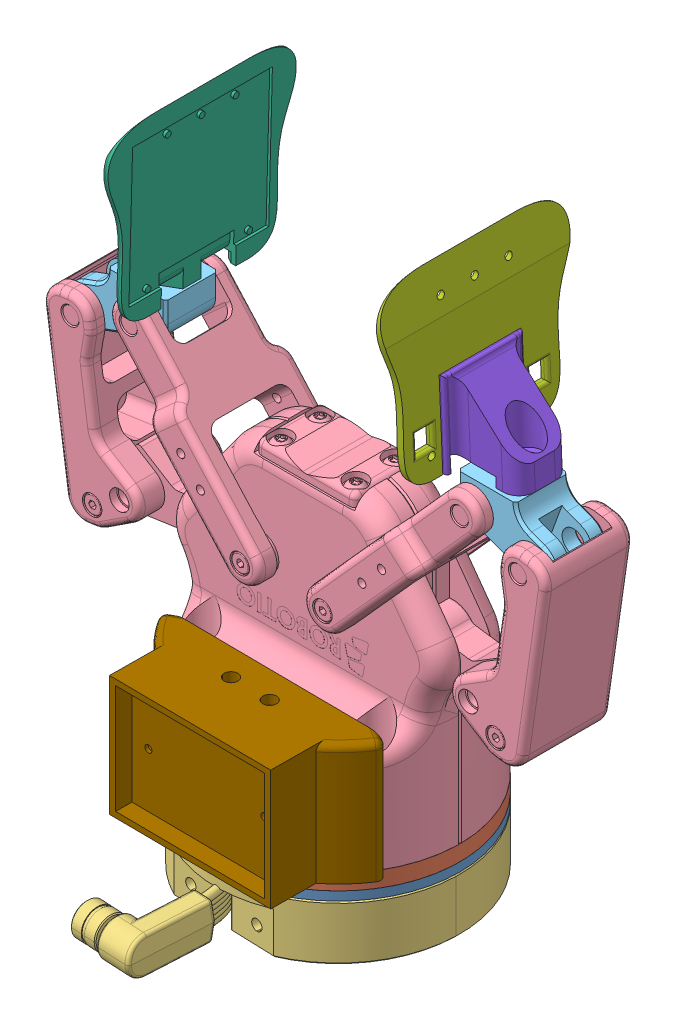
SolidWorks assembly GripperAssembly, configuration Default. Lengths in mm.
Overall size (154.57 188.05 107.75).
12 component instances, 9 part files, 12 mates.
Components (placement in the parent):
- PCB_flange-1: PCB_flange [Default] at (13.3416 26.4791 25.4276) size (75 9.2 71.41)
- PCB_flange_top-1: PCB_flange_top [Default] at (13.3416 33.9791 25.4276) x (1 0 0) z (0 -1 0) size (75 76 7.3)
- IO_20Coupling_20UR_20CB_20190807-1: IO_20Coupling_20UR_20CB_20190807 [Default] at (13.3416 19.4791 25.4276) x (-0.999452 0 -0.033096) z (0 1 0) size (75 105.33 17)
- 2F85-OPENED-NO_FINGER-1: 2F85-OPENED-NO_FINGER [Default] at (13.3416 33.8791 25.4276) size (154.57 113.82 75.02)
  - 2F85-OPENED-NO_20FINGER_20181108.STEP-1: 2F85-OPENED-NO_20FINGER_20181108.STEP [Default] at origin size (154.57 113.82 75.02)
    - C-A01-85-OPENED.STEP-1: C-A01-85-OPENED.STEP [Default] at origin size (154.57 113.32 75.02)
    - C-049-DISTALE_DISTALE.STEP-1: C-049-DISTALE_DISTALE.STEP [Default] at (-50.9079 103.9203 0) x (0.000045 1 0) z (0 0 -1) size (19.02 29.9 16.2)
    - C-049-DISTALE_DISTALE.STEP-2: C-049-DISTALE_DISTALE.STEP [Default] at (50.9079 103.9203 0) x (-0.000045 1 0) z (0 0 1) size (19.02 29.9 16.2)
- IRTouch_rigid-1: IRTouch_rigid [Default] at (-72.4754 198.4459 -64.5202) x (0 0 1) z (-0.026222 -0.999656 0) size (59.45 20.16 56.24)
- IRTouch_flex-1: IRTouch_flex [Default] at (56.9149 151.5392 3.6955) x (0 0 1) z (-0.043664 0.999046 0) size (60.09 4.5 55.96)
- IRTouch_flex_interface-1: IRTouch_flex_interface [Default] at (69.8172 161.6041 44.3771) x (0 0 -1) z (0.043664 -0.999046 0) size (24.8 19.45 26.62)
- Arduino_holder-2: Arduino_holder [Default] at (13.5774 36.0586 25.3763) x (-0.999962 0 -0.008727) z (0.008727 0 -0.999962) size (68.16 37.16 26.52)
Mates (geometry in assembly coordinates):
- Coincident1: coincident anti-aligned: plane of PCB_flange-1 through (13.3416 32.1791 25.4276) normal (0 1 0); plane of PCB_flange_top-1 through (13.3416 32.1791 25.4276) normal (0 -1 0)
- Coincident2: coincident anti-aligned: circle of PCB_flange-1; circle of PCB_flange_top-1
- Concentric1: concentric anti-aligned: circle of PCB_flange-1; circle of IO_20Coupling_20UR_20CB_20190807-1
- Coincident3: coincident anti-aligned: plane of PCB_flange-1 through (13.3416 26.4791 25.4276) normal (0 -1 0); plane of IO_20Coupling_20UR_20CB_20190807-1 through (13.3416 26.4791 25.4276) normal (0 1 0)
- Coincident4: coincident anti-aligned: circle of PCB_flange_top-1; circle of 2F85-OPENED-NO_FINGER-1/2F85-OPENED-NO_20FINGER_20181108.STEP-1/C-A01-85-OPENED.STEP-1
- Coincident6: coincident aligned: line of 2F85-OPENED-NO_FINGER-1/2F85-OPENED-NO_20FINGER_20181108.STEP-1/C-049-DISTALE_DISTALE.STEP-1 through (-49.366 144.3 18.1276) axis (0 0 1); line of IRTouch_rigid-1 through (-49.366 144.3 21.6755) axis (0 0 1)
- Coincident7: coincident anti-aligned: plane of 2F85-OPENED-NO_FINGER-1/2F85-OPENED-NO_20FINGER_20181108.STEP-1/C-049-DISTALE_DISTALE.STEP-1 through (-31.566 144.2992 17.3276) normal (0.000045 1 0); plane of IRTouch_rigid-1 through (-31.0598 144.2992 8.4867) normal (-0.000045 -1 0)
- Coincident8: coincident anti-aligned: plane of 2F85-OPENED-NO_FINGER-1/2F85-OPENED-NO_20FINGER_20181108.STEP-1/C-049-DISTALE_DISTALE.STEP-2 through (58.2492 144.2992 33.5276) normal (-0.000045 1 0); plane of IRTouch_flex_interface-1 through (57.2313 144.2992 36.7495) normal (0.000045 -1 0)
- Coincident9: coincident aligned: line of 2F85-OPENED-NO_FINGER-1/2F85-OPENED-NO_20FINGER_20181108.STEP-1/C-049-DISTALE_DISTALE.STEP-2 through (76.0492 144.3 32.7276) axis (0 0 -1); line of IRTouch_flex_interface-1 through (76.0492 144.3 27.4495) axis (0 0 -1)
- Coincident10: coincident anti-aligned: plane of IRTouch_flex-1 through (55.8128 176.7549 -0.9784) normal (0.999046 0.043664 0); plane of IRTouch_flex_interface-1 through (56.9157 151.5211 45.2379) normal (-0.999046 -0.043664 0)
- Parallel1: parallel aligned: line of 2F85-OPENED-NO_FINGER-1/2F85-OPENED-NO_20FINGER_20181108.STEP-1/C-049-DISTALE_DISTALE.STEP-2 through (58.2492 144.2992 32.7276) axis (0 0 -1); line of IRTouch_flex-1 through (54.8732 152.4498 35.584) axis (0 0 -1)
- Concentric2: concentric anti-aligned: circle of 2F85-OPENED-NO_FINGER-1/2F85-OPENED-NO_20FINGER_20181108.STEP-1/C-A01-85-OPENED.STEP-1; circle of Arduino_holder-2
